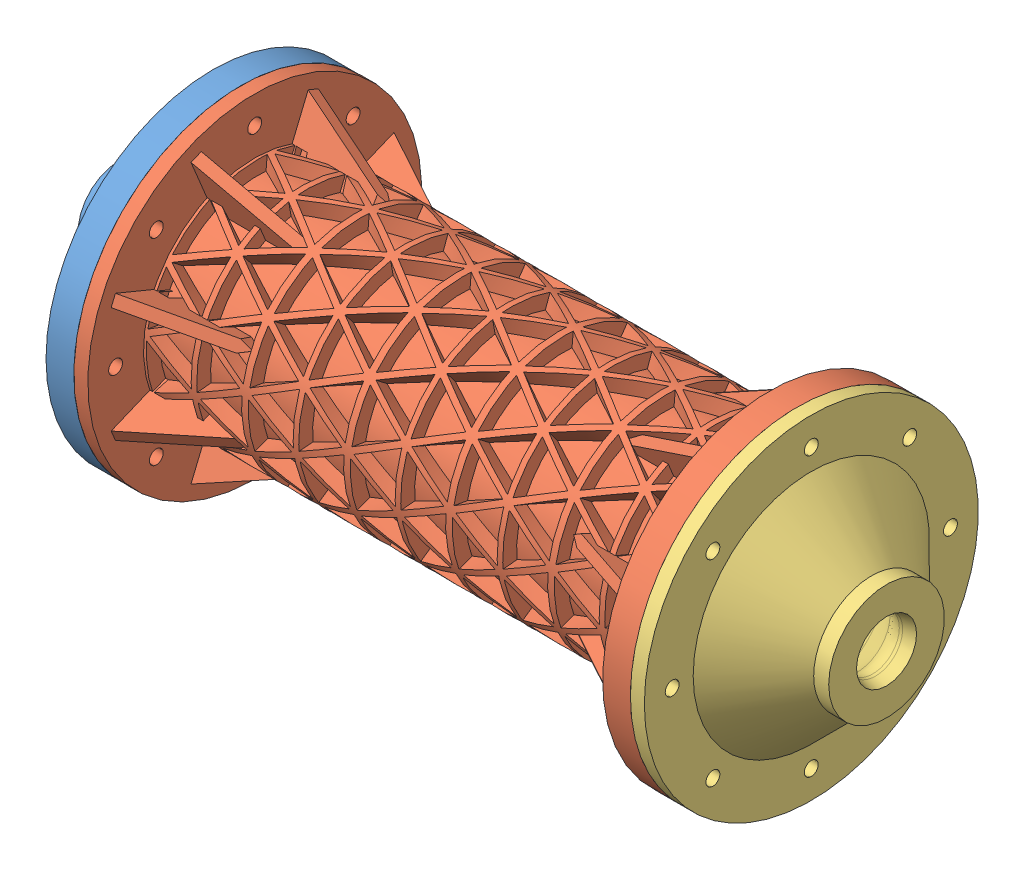
SolidWorks assembly APL_MPE, configuration Default. Lengths in mm.
Overall size (174.99 99.56 99.56).
3 component instances, 3 part files, 7 mates.
Components (placement in the parent):
- APL_PME_dome_injector-1: APL_PME_dome_injector [Default] at origin size (27.65 76.2 76.2)
- APL_PME_chamber-1: APL_PME_chamber [Default] at (127 0 0) x (1 0 0) z (0 -0.382683 0.92388) size (127 76.2 76.2)
- nozzle1-1: nozzle1 [Default] at (127 0 0) size (20.34 76.2 76.2)
Mates (geometry in assembly coordinates):
- Coincident1: coordinate: point of APL_PME_dome_injector-1
- Coincident2: coincident anti-aligned: plane of APL_PME_dome_injector-1 through (0 38.1 0) normal (1 0 0); plane of APL_PME_chamber-1 through (0 17.5999 7.2901) normal (-1 0 0)
- Coincident4: coincident anti-aligned: plane of APL_PME_chamber-1 through (127 35.1998 14.5802) normal (1 0 0); plane of nozzle1-1 through (127 19.05 0) normal (-1 0 0)
- Coincident6: coincident aligned: circle of APL_PME_chamber-1; circle of nozzle1-1
- Concentric3: concentric anti-aligned: cylinder of APL_PME_dome_injector-1 through (-8.5995 0 0) axis (1 0 0) radius 38.1; cylinder of APL_PME_chamber-1 through (-25.49 0 0) axis (-1 0 0) radius 38.1
- Concentric4: concentric aligned: cylinder of APL_PME_dome_injector-1 through (0 22.4506 22.4506) axis (1 0 0) radius 1.5875; cylinder of APL_PME_chamber-1 through (127 22.4506 22.4506) axis (1 0 0) radius 1.5875
- Concentric5: concentric aligned: cylinder of APL_PME_chamber-1 through (127 22.4506 22.4506) axis (1 0 0) radius 1.5875; cylinder of nozzle1-1 through (130.175 22.4506 22.4506) axis (1 0 0) radius 1.5875
